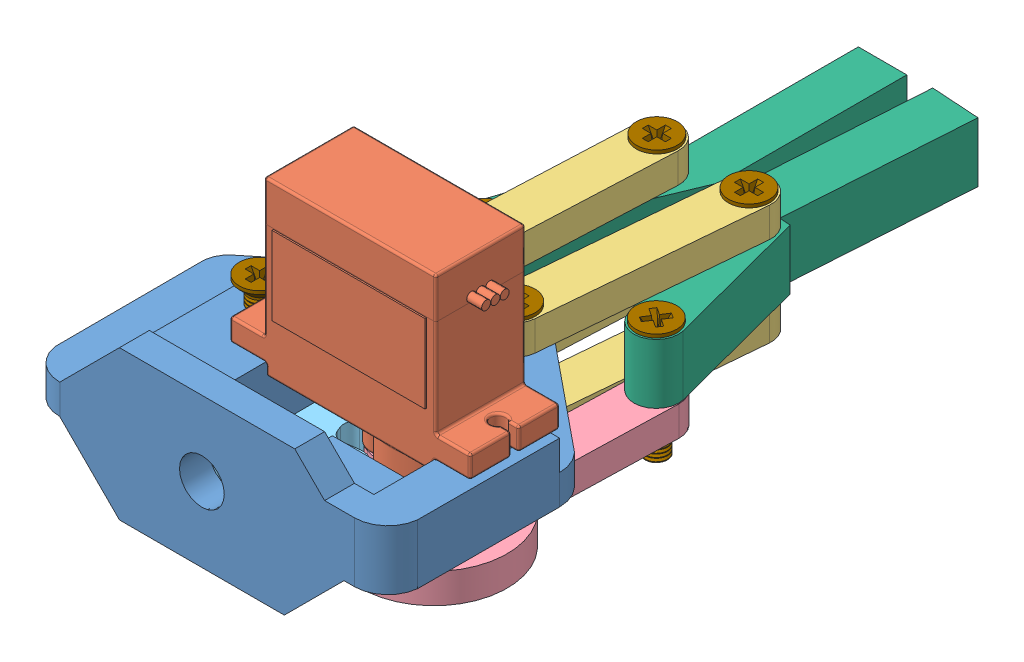
SolidWorks assembly Ensamblaje-Garra, configuration Predeterminado. Lengths in mm.
Overall size (48.52 41.05 92.66).
19 component instances, 9 part files, 42 mates.
Components (placement in the parent):
- Base-De-Garra-1: Base-De-Garra [Predeterminado] at origin size (48.52 20 39)
- MG90S-Servo-1: MG90S-Servo [Default] at (7.6047 29.5 1.0784) x (1 0 0) z (0 0 -1) size (32.2 32.5 12.4)
- Conector-Garra1-1: Conector-Garra1 [Predeterminado] at (-5.6809 4 -30.393) x (-0.044663 0 0.999002) z (-0.999002 0 -0.044663) size (35 4 6)
- Engranaje2-Garra-1: Engranaje2-Garra [Predeterminado] at (11.323 -8 -8.6731) x (0.999602 0 0.028201) z (-0.028201 0 0.999602) size (23.26 4 45.53)
- Engranaje-Garra-1: Engranaje-Garra [Predeterminado] at (-8.821 -8 -8.0433) x (0.999017 0 0.044338) z (-0.044338 0 0.999017) size (24.22 4 46.45)
- Pinza-Garra-1: Pinza-Garra [Predeterminado] at (-5.6485 -4 -48.9603) x (1 0 0.000341) z (-0.000341 0 1) size (14.5 8 47.96)
- Separador-Engrane-Base-1: Separador-Engrane-Base [Predeterminado] at (-10.9453 -4 0.7523) size (5.99 4 5.99)
- Soporte-Garra-1: Soporte-Garra [Predeterminado] at (0.5047 -4 -16.9902) x (1 0 0) z (0 0 1) size (25 4 6.56)
- Conector-Garra1-2: Conector-Garra1 [Predeterminado] at (-5.6809 -8 -30.393) x (-0.044663 0 0.999002) z (-0.999002 0 -0.044663) size (35 4 6)
- Conector-Garra1-3: Conector-Garra1 [Predeterminado] at (8.9197 -8 -31.159) x (0.087453 0 -0.996169) z (0.996169 0 0.087453) size (35 4 6)
- Conector-Garra1-4: Conector-Garra1 [Predeterminado] at (8.9197 4 -31.159) x (0.087453 0 -0.996169) z (0.996169 0 0.087453) size (35 4 6)
- Pinza-Garra-2: Pinza-Garra [Predeterminado] at (11.0159 4 -48.7403) x (-0.997891 0 -0.064917) z (-0.064917 0 0.997891) size (14.5 8 47.96)
- flat head screw_am-1: flat head screw_am [B18.6.7M - M3 x 0.5 x 16 Type I Cross Recessed FHMS --16S] at (-3.6537 8.45 -45.311) x (0 -1 0) z (0 0 1) size (16 5.5 5.5)
- flat head screw_am-2: flat head screw_am [B18.6.7M - M3 x 0.5 x 16 Type I Cross Recessed FHMS --16S] at (-9.6595 4.45 -28.3431) x (0 -1 0) z (0 0 1) size (16 5.5 5.5)
- flat head screw_am-3: flat head screw_am [B18.6.7M - M3 x 0.5 x 16 Type I Cross Recessed FHMS --16S] at (-4.9453 8.45 -16.3416) x (0 -1 0) z (0 0 1) size (16 5.5 5.5)
- flat head screw_am-4: flat head screw_am [B18.6.7M - M3 x 0.5 x 16 Type I Cross Recessed FHMS --16S] at (6.2547 8.45 -16.3416) x (0 -1 0) z (0 0 1) size (16 5.5 5.5)
- flat head screw_am-5: flat head screw_am [B18.6.7M - M3 x 0.5 x 16 Type I Cross Recessed FHMS --16S] at (8.7872 8.45 -45.229) x (0 -1 0) z (0 0 1) size (16 5.5 5.5)
- flat head screw_am-6: flat head screw_am [B18.6.7M - M3 x 0.5 x 16 Type I Cross Recessed FHMS --16S] at (-10.9453 11.45 0.6284) x (0 -1 0) z (0 0 1) size (16 5.5 5.5)
- flat head screw_am-7: flat head screw_am [B18.6.7M - M3 x 0.5 x 16 Type I Cross Recessed FHMS --16S] at (13.6699 4.45 -27.9163) x (0 -1 0) z (-0.546944 0 0.837169) size (16 5.5 5.5)
Mates (geometry in assembly coordinates):
- Coincidente1: coincident: plane of Base-De-Garra-1 through (0 8 0) normal (0 1 0); plane of MG90S-Servo-1 through (7.6047 8 1.0784) normal (0 -1 0)
- Coincidente2: coincident: plane of Base-De-Garra-1 through (18.8547 4 -5.8216) normal (-1 0 0); plane of MG90S-Servo-1 through (18.8547 6.5 -4.9216) normal (1 0 0)
- Coincidente3: coincident: plane of Base-De-Garra-1 through (5.2547 4 7.0784) normal (0 0 -1); plane of MG90S-Servo-1 through (-3.8953 11 7.0784) normal (0 0 1)
- Coincidente4: coincident: plane of Base-De-Garra-1 through (-19.2453 0 14.6284) normal (0 -1 0); plane of Soporte-Garra-1 through (-5.1827 0 -15.3511) normal (0 1 0)
- Concéntrica4: concentric: cylinder of Base-De-Garra-1 through (-4.9453 4 -16.3416) axis (0 -1 0) radius 1.5; cylinder of Soporte-Garra-1 through (-4.9453 0 -16.3416) axis (0 -1 0) radius 1.5
- Concéntrica5: concentric: cylinder of Base-De-Garra-1 through (6.2547 4 -16.3416) axis (0 -1 0) radius 1.5; cylinder of Soporte-Garra-1 through (6.2547 0 -16.3416) axis (0 -1 0) radius 1.5
- Concéntrica6: concentric: cylinder of Base-De-Garra-1 through (-4.9453 4 -16.3416) axis (0 -1 0) radius 1.5; cylinder of Conector-Garra1-1 through (-4.9453 8 -16.3416) axis (0 -1 0) radius 1.5
- Coincidente5: coincident: plane of Base-De-Garra-1 through (-19.2453 4 14.6284) normal (0 1 0); plane of Conector-Garra1-1 through (-3.65 4 -45.3127) normal (0 -1 0)
- Coincidente7: coincident: plane of Engranaje-Garra-1 through (-8.821 -4 -8.0433) normal (0 1 0); plane of Separador-Engrane-Base-1 through (-10.9453 -4 0.6284) normal (0 -1 0)
- Concéntrica8: concentric: cylinder of Engranaje-Garra-1 through (-10.9453 -4 0.6284) axis (0 -1 0) radius 1.5; cylinder of Separador-Engrane-Base-1 through (-10.9453 0 0.6284) axis (0 -1 0) radius 1.4956
- Concéntrica9: concentric: cylinder of Base-De-Garra-1 through (-10.9453 4 0.6284) axis (0 -1 0) radius 1.5; cylinder of Engranaje-Garra-1 through (-10.9453 -4 0.6284) axis (0 -1 0) radius 1.5
- Coincidente8: coincident: plane of Base-De-Garra-1 through (-19.2453 0 14.6284) normal (0 -1 0); plane of Separador-Engrane-Base-1 through (-10.9453 0 0.6284) normal (0 1 0)
- Concéntrica11: concentric: cylinder of Conector-Garra1-1 through (-3.6537 8 -45.311) axis (0 -1 0) radius 1.4985; cylinder of Pinza-Garra-1 through (-3.6537 4 -45.311) axis (0 -1 0) radius 1.5
- Concéntrica12: concentric: cylinder of Engranaje-Garra-1 through (-9.6595 -4 -28.3431) axis (0 -1 0) radius 1.5; cylinder of Pinza-Garra-1 through (-9.6595 4 -28.3431) axis (0 -1 0) radius 1.5
- Coincidente9: coincident: plane of Pinza-Garra-1 through (-9.6558 -4 -28.3538) normal (0 -1 0); plane of Conector-Garra1-2 through (-3.65 -4 -45.3127) normal (0 1 0)
- Concéntrica13: concentric: cylinder of Pinza-Garra-1 through (-3.6537 4 -45.311) axis (0 -1 0) radius 1.5; cylinder of Conector-Garra1-2 through (-3.6537 -4 -45.311) axis (0 -1 0) radius 1.4985
- Concéntrica14: concentric: cylinder of Soporte-Garra-1 through (-4.9453 0 -16.3416) axis (0 -1 0) radius 1.5; cylinder of Conector-Garra1-2 through (-4.9453 -4 -16.3416) axis (0 -1 0) radius 1.5
- Concéntrica15: concentric: cylinder of Soporte-Garra-1 through (6.2547 0 -16.3416) axis (0 -1 0) radius 1.5; cylinder of Conector-Garra1-3 through (6.2547 -4 -16.3416) axis (0 -1 0) radius 1.4985
- Coincidente10: coincident: plane of Soporte-Garra-1 through (-5.1827 -4 -15.3511) normal (0 -1 0); plane of Conector-Garra1-3 through (6.251 -4 -16.3401) normal (0 1 0)
- Coincidente11: coincident: plane of Conector-Garra1-3 through (6.251 -4 -16.3401) normal (0 1 0); plane of Pinza-Garra-2 through (13.6699 -4 -27.9163) normal (0 -1 0)
- Concéntrica16: concentric: cylinder of Conector-Garra1-3 through (8.7872 -4 -45.229) axis (0 -1 0) radius 1.5; cylinder of Pinza-Garra-2 through (8.7872 -4 -45.229) axis (0 1 0) radius 1.5
- Concéntrica17: concentric: cylinder of Engranaje2-Garra-1 through (13.6729 -4 -27.9053) axis (0 -1 0) radius 1.4982; cylinder of Pinza-Garra-2 through (13.6729 -4 -27.9053) axis (0 1 0) radius 1.5
- Concéntrica18: concentric: cylinder of Conector-Garra1-4 through (8.7872 8 -45.229) axis (0 -1 0) radius 1.5; cylinder of Pinza-Garra-2 through (8.7872 -4 -45.229) axis (0 1 0) radius 1.5
- Coincidente12: coincident: plane of Conector-Garra1-4 through (6.251 4 -16.3401) normal (0 -1 0); plane of Pinza-Garra-2 through (13.6699 4 -27.9163) normal (0 1 0)
- Concéntrica19: concentric: cylinder of Base-De-Garra-1 through (6.2547 4 -16.3416) axis (0 -1 0) radius 1.5; cylinder of Conector-Garra1-4 through (6.2547 8 -16.3416) axis (0 -1 0) radius 1.4985
- Concéntrica20: concentric: cylinder of Conector-Garra1-1 through (-3.6537 8 -45.311) axis (0 -1 0) radius 1.4985; cone of flat head screw_am-1 through (-3.6537 8 -45.311) axis (0 -1 0)
- Concéntrica21: concentric: cylinder of Pinza-Garra-1 through (-9.6595 4 -28.3431) axis (0 -1 0) radius 1.5; cone of flat head screw_am-2 through (-9.6595 4 -28.3431) axis (0 -1 0)
- Concéntrica22: concentric: cylinder of Conector-Garra1-1 through (-4.9453 8 -16.3416) axis (0 -1 0) radius 1.5; cone of flat head screw_am-3 through (-4.9453 8 -16.3416) axis (0 -1 0)
- Concéntrica23: concentric: cylinder of Conector-Garra1-4 through (6.2547 8 -16.3416) axis (0 -1 0) radius 1.4985; cone of flat head screw_am-4 through (6.2547 8 -16.3416) axis (0 -1 0)
- Concéntrica24: concentric: cylinder of Conector-Garra1-4 through (8.7872 8 -45.229) axis (0 -1 0) radius 1.5; cone of flat head screw_am-5 through (8.7872 8 -45.229) axis (0 -1 0)
- Concéntrica25: concentric: cylinder of Base-De-Garra-1 through (-10.9453 4 0.6284) axis (0 -1 0) radius 1.5; cone of flat head screw_am-6 through (-10.9453 11 0.6284) axis (0 -1 0)
- Coincidente13: coincident: axis of Pinza-Garra-2 through (13.6699 -4 -27.9163) axis (0 1 0); axis of flat head screw_am-7 through (13.6699 -8.8893 -27.9163) axis (0 1 0)
- Coincidente14: coincident: plane of Pinza-Garra-2 through (13.6699 4 -27.9163) normal (0 1 0); circle of flat head screw_am-7
- Coincidente15: coincident: plane of Conector-Garra1-4 through (6.251 8 -16.3401) normal (0 1 0); circle of flat head screw_am-5
- Coincidente16: coincident: plane of Conector-Garra1-4 through (6.251 8 -16.3401) normal (0 1 0); circle of flat head screw_am-4
- Coincidente17: coincident: plane of Conector-Garra1-1 through (-3.65 8 -45.3127) normal (0 1 0); circle of flat head screw_am-1
- Coincidente18: coincident: plane of Conector-Garra1-1 through (-3.65 8 -45.3127) normal (0 1 0); circle of flat head screw_am-3
- Coincidente19: coincident: plane of MG90S-Servo-1 through (7.6047 11 1.0784) normal (0 1 0); circle of flat head screw_am-6
- Coincidente20: coincident: plane of Pinza-Garra-1 through (-9.6558 4 -28.3538) normal (0 1 0); circle of flat head screw_am-2
- Coincidente21: coincident: plane of Soporte-Garra-1 through (-5.1827 -4 -15.3511) normal (0 -1 0); plane of Conector-Garra1-2 through (-3.65 -4 -45.3127) normal (0 1 0)
- Concéntrica26: concentric: cylinder of MG90S-Servo-1 through (12.8547 -0.5 1.0784) axis (0 -1 0) radius 1.25; cylinder of Engranaje2-Garra-1 through (12.8547 -4 1.0784) axis (0 -1 0) radius 2.9962
- Coincidente24: coincident: plane of Engranaje2-Garra-1 through (8.5918 -4 -10.1273) normal (0 1 0); plane of Pinza-Garra-2 through (13.6699 -4 -27.9163) normal (0 -1 0)
